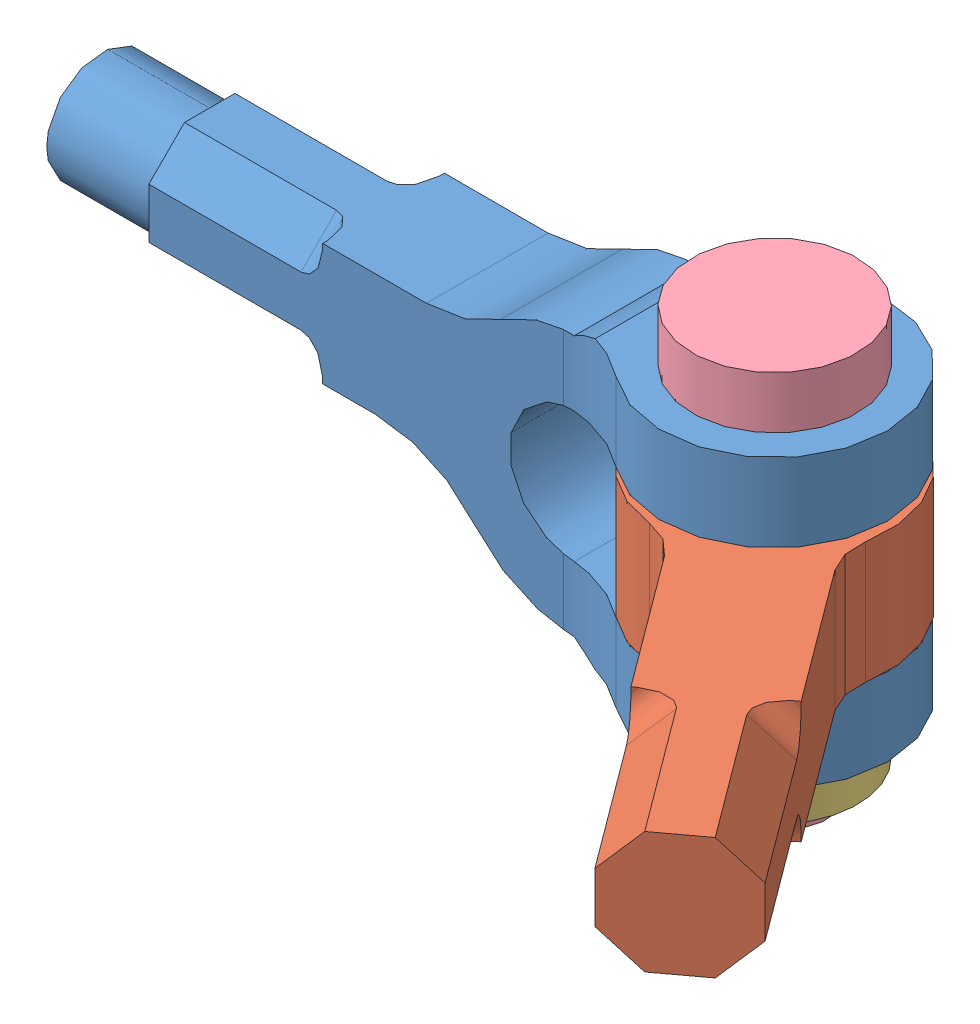
SolidWorks assembly Assem9, configuration Default. Lengths in mm.
Overall size (238.43 96 136.2).
5 component instances, 5 part files, 8 mates.
Components (placement in the parent):
- Part5-1: Part5 [Default] at (2.0975 13.2236 -1.7439) size (181 66 52)
- Part4-1: Part4 [Default] at (8.3943 6.875 24.2561) x (0.595729 0 0.803185) z (0 1 0) size (131 52 28)
- Part3-1: Part3 [Default] at (8.3943 -37.125 24.2561) x (0.059566 0 0.998224) z (0 1 0) size (38 38 12)
- Part1-1: Part1 [Default] at (8.3943 40.875 24.2561) x (0.059566 0 0.998224) z (0 -1 0) size (38 38 96)
- Part2-1: Part2 [Default] at (8.4883 -31.125 25.8313) x (-0.105749 -0.994373 0.00631) z (0.059566 0 0.998224) size (8.1 8.1 20)
Mates (geometry in assembly coordinates):
- Coincident3: coincident anti-aligned: plane of Part5-1 through (2.0975 -7.125 50.2561) normal (0 1 0); plane of Part4-1 through (8.3943 -7.125 24.2561) normal (0 -1 0)
- Concentric1: concentric anti-aligned: cylinder of Part5-1 through (8.3943 -39.125 24.2561) axis (0 1 0) radius 26; cylinder of Part4-1 through (8.3943 20.875 24.2561) axis (0 -1 0) radius 26
- Coincident4: coincident anti-aligned: plane of Part5-1 through (2.0975 -25.125 50.2561) normal (0 -1 0); plane of Part3-1 through (8.3943 -25.125 24.2561) normal (0 1 0)
- Coincident5: coincident anti-aligned: circle of Part5-1; circle of Part3-1
- Concentric2: concentric aligned: cylinder of Part5-1 through (8.3943 -39.125 24.2561) axis (0 1 0) radius 12.5; cylinder of Part1-1 through (8.3943 -43.125 24.2561) axis (0 1 0) radius 12.5
- Coincident6: coincident anti-aligned: plane of Part5-1 through (2.0975 40.875 50.2561) normal (0 1 0); plane of Part1-1 through (8.3943 40.875 24.2561) normal (0 -1 0)
- Concentric3: concentric aligned: cylinder of Part3-1 through (6.369 -31.125 -9.6836) axis (0.059566 0 0.998224) radius 3; cylinder of Part1-1 through (5.8925 -31.125 -17.6694) axis (0.059566 0 0.998224) radius 3
- Concentric4: concentric anti-aligned: cylinder of Part3-1 through (6.369 -31.125 -9.6836) axis (0.059566 0 0.998224) radius 3; cone of Part2-1 through (8.4883 -31.125 25.8313) axis (-0.059566 0 -0.998224)
